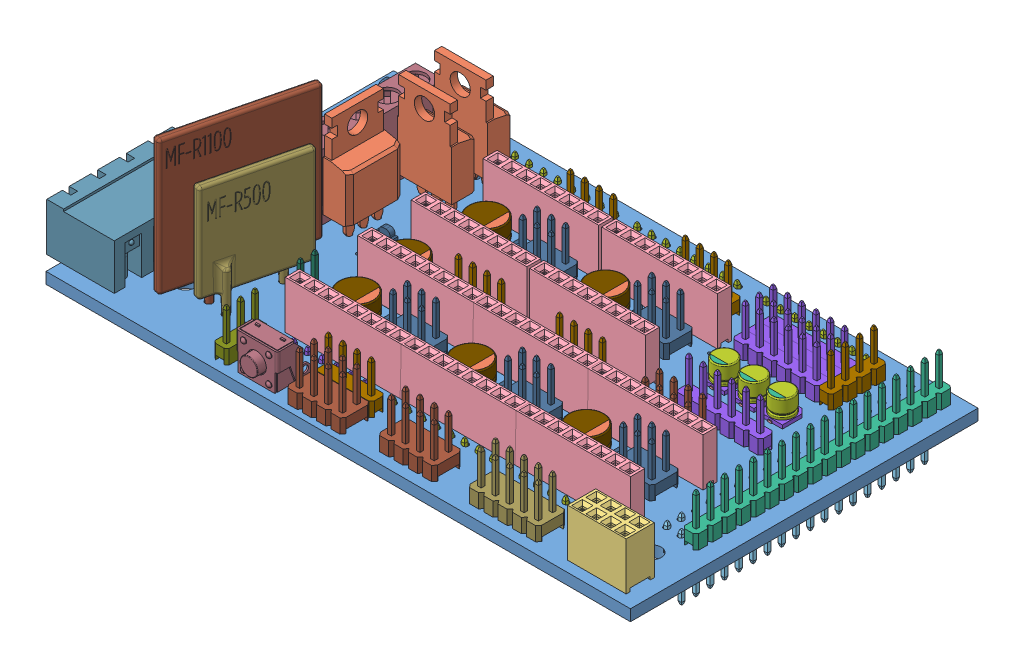
SolidWorks assembly RAMPS1_4, configuration Default. Lengths in mm.
Overall size (106.38 37.63 61.76).
107 component instances, 31 part files, 0 mates.
Components (placement in the parent):
- RAMPS1_4-1: RAMPS1_4 [Default] at (-38.4421 2.2803 -26.502) x (1 0 0) z (0 1 0) size (103.85 61.76 2)
- User Library-POWER MOSFET, NON-SURFACE-MOUNT-1: User Library-POWER MOSFET, NON-SURFACE-MOUNT [Default] at (-31.1839 8.1207 -13.4695) x (-1 0 0) z (0 -1 0) size (9.65 4.5 28.38)
- female_header_a-bl254-dg-g08d-1: female_header_a-bl254-dg-g08d [Default] at (41.0481 4.2584 25.6311) size (10.41 11.65 5)
- female_header_a-bl254-eg-g08d-2: female_header_a-bl254-eg-g08d [Default] at (6.3865 4.2963 -6.1397) size (20.57 11.65 2.5)
- female_header_a-bl254-eg-g08d-10: female_header_a-bl254-eg-g08d [Default] at (26.827 4.2963 16.9325) size (20.57 11.65 2.5)
- pin_header_aw254-dg-g36d-1: pin_header_aw254-dg-g36d [Default] at (40.9113 2.2239 -7.3898) x (0 0 1) z (-1 0 0) size (45.72 11.5 5.08)
- pin_header_aw140-eg-g18d-1: pin_header_aw140-eg-g18d [Default] at (44.7498 4.3175 -7.3949) x (0 0 -1) z (-1 0 0) size (45.62 11.2 2.5)
- pin_header_aw140-eg-g08d-1: pin_header_aw140-eg-g08d [Default] at (28.1033 2.2803 19.4616) size (20.22 11.2 2.5)
- pin_header_aw140-eg-g08d-2: pin_header_aw140-eg-g08d [Default] at (5.0609 2.2803 19.4616) size (20.22 11.2 2.5)
- pin_header_aw140-eg-g08d-3: pin_header_aw140-eg-g08d [Default] at (-0.0426 2.2803 -29.0108) size (20.22 11.2 2.5)
- pin_header_aw140-eg-g08d-4: pin_header_aw140-eg-g08d [Default] at (22.8713 2.2803 -29.0108) size (20.22 11.2 2.5)
- pin_header_aw140-eg-g08d-5: pin_header_aw140-eg-g08d [Default] at (-21.773 2.2803 -29.0108) size (20.22 11.2 2.5)
- pin_header_aw140-eg-g06d-1: pin_header_aw140-eg-g06d [Default] at (29.4382 4.2803 -6.1813) x (-1 0 0) z (0 0 1) size (15.14 11.2 2.5)
- pin_header_aw140-eg-g06d-2: pin_header_aw140-eg-g06d [Default] at (26.2798 4.262 -19.3796) x (-1 0 0) z (0 0 1) size (15.14 11.2 2.5)
- pin_header_aw140-eg-g04d-1: pin_header_aw140-eg-g04d [Default] at (8.4073 4.2803 -24.0519) x (-1 0 0) z (0 0 1) size (10.06 11.2 2.5)
- pin_header_aw140-eg-g04d-2: pin_header_aw140-eg-g04d [Default] at (-12.021 4.262 -24.0519) x (-1 0 0) z (0 0 1) size (10.06 11.2 2.5)
- pin_header_aw140-eg-g04d-3: pin_header_aw140-eg-g04d [Default] at (-8.9039 4.262 -1.0355) x (-1 0 0) z (0 0 1) size (10.06 11.2 2.5)
- pin_header_aw140-eg-g04d-4: pin_header_aw140-eg-g04d [Default] at (9.0685 4.262 -1.0355) x (-1 0 0) z (0 0 1) size (10.06 11.2 2.5)
- pin_header_aw140-eg-g04d-5: pin_header_aw140-eg-g04d [Default] at (-8.3709 4.2803 22.5944) x (-1 0 0) z (0 0 1) size (10.06 11.2 2.5)
- pin_header_aw254-dg-g06d-1: pin_header_aw254-dg-g06d [Default] at (-10.2573 4.2803 9.2323) x (-1 0 0) z (0 0 1) size (7.62 11.5 5.08)
- pin_header_aw254-dg-g06d-2: pin_header_aw254-dg-g06d [Default] at (10.1683 4.262 9.2323) x (-1 0 0) z (0 0 1) size (7.62 11.5 5.08)
- pin_header_aw254-dg-g06d-3: pin_header_aw254-dg-g06d [Default] at (30.6527 4.262 9.2323) x (-1 0 0) z (0 0 1) size (7.62 11.5 5.08)
- pin_header_aw254-dg-g06d-4: pin_header_aw254-dg-g06d [Default] at (10.1683 4.262 -13.7827) x (-1 0 0) z (0 0 1) size (7.62 11.5 5.08)
- pin_header_aw254-dg-g06d-5: pin_header_aw254-dg-g06d [Default] at (-10.2204 4.262 -13.7827) x (-1 0 0) z (0 0 1) size (7.62 11.5 5.08)
- pin_header_aw254-dg-g08d-1: pin_header_aw254-dg-g08d [Default] at (7.0775 4.2803 25.6017) x (-1 0 0) z (0 0 1) size (10.16 11.5 5.08)
- pin_header_aw254-dg-g08d-2: pin_header_aw254-dg-g08d [Default] at (-8.3884 4.2803 26.4286) x (-1 0 0) z (0 0 1) size (10.16 11.5 5.08)
- pin_header_aw254-dg-g10d-1: pin_header_aw254-dg-g10d [Default] at (24.3252 4.2803 25.6162) x (-1 0 0) z (0 0 1) size (12.7 11.5 5.08)
- pin_header_aw140-eg-g04d-6: pin_header_aw140-eg-g04d [Default] at (35.1498 4.262 -23.186) x (0 0 -1) z (-1 0 0) size (10.06 11.2 2.5)
- pin_header_aw140-eg-g06d-5: pin_header_aw140-eg-g06d [Default] at (-15.2568 2.2803 19.3514) size (15.14 11.2 2.5)
- terminal_blocks_a-tb500-to06-1: terminal_blocks_a-tb500-to06 [Default] at (-37.528 4.2803 -9.8658) x (0 0 1) z (-1 0 0) size (30.6 13.8 8.3)
- terminal_blocks_a-tb508-oq04ch-1: terminal_blocks_a-tb508-oq04ch [Default] at (-57.4712 4.2803 16.3679) x (0 0 1) z (-1 0 0) size (22.32 12.5 12)
- pin_header_aw254-dg-g08d-3: pin_header_aw254-dg-g08d [Default] at (26.8817 4.262 0.2918) x (-1 0 0) z (0 0 1) size (10.16 11.5 5.08)
- pin_header_aw140-eg-g02d-1: pin_header_aw140-eg-g02d [Default] at (-26.0896 4.2803 12.3888) x (0 0 1) z (1 0 0) size (4.98 11.2 2.5)
- pin_header_aw140-eg-g03d-1: pin_header_aw140-eg-g03d [Default] at (-25.5036 4.2803 24.8649) x (0 0 1) z (1 0 0) size (7.52 11.2 2.5)
- User Library-CAPSMD6_3x3_9-1: User Library-CAPSMD6_3x3_9 [Default] at (-23.4034 4.2803 -13.8521) x (0 0 -1) z (0 1 0) size (6.6 7 3.91)
  - User Library-CAPSMD6_3x3_9_CAP003-1: User Library-CAPSMD6_3x3_9_CAP003 [Default] at origin size (0.65 2.6 0.32)
  - User Library-CAPSMD6_3x3_9_CAP-1: User Library-CAPSMD6_3x3_9_CAP [Default] at origin size (6.3 6.3 3.26)
  - User Library-CAPSMD6_3x3_9_CAP001-1: User Library-CAPSMD6_3x3_9_CAP001 [Default] at origin size (6.6 6.6 0.64)
  - User Library-CAPSMD6_3x3_9_CAP002-1: User Library-CAPSMD6_3x3_9_CAP002 [Default] at origin size (5.11 1.47 0.01)
  - User Library-CAPSMD6_3x3_9_CAP004-1: User Library-CAPSMD6_3x3_9_CAP004 [Default] at origin size (0.65 2.6 0.32)
- User Library-CAPSMD6_3x3_9-2: User Library-CAPSMD6_3x3_9 [Default] at (-2.2688 4.2803 -13.8521) x (0 0 -1) z (0 1 0) size (6.6 7 3.91)
  - User Library-CAPSMD6_3x3_9_CAP003-1: User Library-CAPSMD6_3x3_9_CAP003 [Default] at origin size (0.65 2.6 0.32)
  - User Library-CAPSMD6_3x3_9_CAP-1: User Library-CAPSMD6_3x3_9_CAP [Default] at origin size (6.3 6.3 3.26)
  - User Library-CAPSMD6_3x3_9_CAP001-1: User Library-CAPSMD6_3x3_9_CAP001 [Default] at origin size (6.6 6.6 0.64)
  - User Library-CAPSMD6_3x3_9_CAP002-1: User Library-CAPSMD6_3x3_9_CAP002 [Default] at origin size (5.11 1.47 0.01)
  - User Library-CAPSMD6_3x3_9_CAP004-1: User Library-CAPSMD6_3x3_9_CAP004 [Default] at origin size (0.65 2.6 0.32)
- User Library-CAPSMD6_3x3_9-3: User Library-CAPSMD6_3x3_9 [Default] at (-2.8787 4.2803 9.2865) x (0 0 -1) z (0 1 0) size (6.6 7 3.91)
  - User Library-CAPSMD6_3x3_9_CAP003-1: User Library-CAPSMD6_3x3_9_CAP003 [Default] at origin size (0.65 2.6 0.32)
  - User Library-CAPSMD6_3x3_9_CAP-1: User Library-CAPSMD6_3x3_9_CAP [Default] at origin size (6.3 6.3 3.26)
  - User Library-CAPSMD6_3x3_9_CAP001-1: User Library-CAPSMD6_3x3_9_CAP001 [Default] at origin size (6.6 6.6 0.64)
  - User Library-CAPSMD6_3x3_9_CAP002-1: User Library-CAPSMD6_3x3_9_CAP002 [Default] at origin size (5.11 1.47 0.01)
  - User Library-CAPSMD6_3x3_9_CAP004-1: User Library-CAPSMD6_3x3_9_CAP004 [Default] at origin size (0.65 2.6 0.32)
- User Library-CAPSMD6_3x3_9-4: User Library-CAPSMD6_3x3_9 [Default] at (-23.2996 4.2803 9.2865) x (0 0 -1) z (0 1 0) size (6.6 7 3.91)
  - User Library-CAPSMD6_3x3_9_CAP003-1: User Library-CAPSMD6_3x3_9_CAP003 [Default] at origin size (0.65 2.6 0.32)
  - User Library-CAPSMD6_3x3_9_CAP-1: User Library-CAPSMD6_3x3_9_CAP [Default] at origin size (6.3 6.3 3.26)
  - User Library-CAPSMD6_3x3_9_CAP001-1: User Library-CAPSMD6_3x3_9_CAP001 [Default] at origin size (6.6 6.6 0.64)
  - User Library-CAPSMD6_3x3_9_CAP002-1: User Library-CAPSMD6_3x3_9_CAP002 [Default] at origin size (5.11 1.47 0.01)
  - User Library-CAPSMD6_3x3_9_CAP004-1: User Library-CAPSMD6_3x3_9_CAP004 [Default] at origin size (0.65 2.6 0.32)
- User Library-CAPSMD6_3x3_9-5: User Library-CAPSMD6_3x3_9 [Default] at (17.5196 4.2803 9.2865) x (0 0 -1) z (0 1 0) size (6.6 7 3.91)
  - User Library-CAPSMD6_3x3_9_CAP003-1: User Library-CAPSMD6_3x3_9_CAP003 [Default] at origin size (0.65 2.6 0.32)
  - User Library-CAPSMD6_3x3_9_CAP-1: User Library-CAPSMD6_3x3_9_CAP [Default] at origin size (6.3 6.3 3.26)
  - User Library-CAPSMD6_3x3_9_CAP001-1: User Library-CAPSMD6_3x3_9_CAP001 [Default] at origin size (6.6 6.6 0.64)
  - User Library-CAPSMD6_3x3_9_CAP002-1: User Library-CAPSMD6_3x3_9_CAP002 [Default] at origin size (5.11 1.47 0.01)
  - User Library-CAPSMD6_3x3_9_CAP004-1: User Library-CAPSMD6_3x3_9_CAP004 [Default] at origin size (0.65 2.6 0.32)
- User Library-CAPSMD6_3x3_9-6: User Library-CAPSMD6_3x3_9 [Default] at (-24.6073 4.2803 -1.0117) x (0 0 -1) z (0 1 0) size (6.6 7 3.91)
  - User Library-CAPSMD6_3x3_9_CAP003-1: User Library-CAPSMD6_3x3_9_CAP003 [Default] at origin size (0.65 2.6 0.32)
  - User Library-CAPSMD6_3x3_9_CAP-1: User Library-CAPSMD6_3x3_9_CAP [Default] at origin size (6.3 6.3 3.26)
  - User Library-CAPSMD6_3x3_9_CAP001-1: User Library-CAPSMD6_3x3_9_CAP001 [Default] at origin size (6.6 6.6 0.64)
  - User Library-CAPSMD6_3x3_9_CAP002-1: User Library-CAPSMD6_3x3_9_CAP002 [Default] at origin size (5.11 1.47 0.01)
  - User Library-CAPSMD6_3x3_9_CAP004-1: User Library-CAPSMD6_3x3_9_CAP004 [Default] at origin size (0.65 2.6 0.32)
- User Library-CAPSMD4x3_9-1: User Library-CAPSMD4x3_9 [Default] at (22.2937 4.2803 -15.1178) x (1 0 0) z (0 1 0) size (4.3 4.6 3.91)
  - User Library-CAPSMD4x3_9_CAPSMD4x3_9003-1: User Library-CAPSMD4x3_9_CAPSMD4x3_9003 [Default] at origin size (0.65 1.8 0.32)
  - User Library-CAPSMD4x3_9_CAPSMD4x3_9004-1: User Library-CAPSMD4x3_9_CAPSMD4x3_9004 [Default] at origin size (0.65 1.8 0.32)
  - User Library-CAPSMD4x3_9_CAPSMD4x3_9002-1: User Library-CAPSMD4x3_9_CAPSMD4x3_9002 [Default] at origin size (3.12 0.9 0.01)
  - User Library-CAPSMD4x3_9_CAPSMD4x3_9001-1: User Library-CAPSMD4x3_9_CAPSMD4x3_9001 [Default] at origin size (4 4 3.26)
  - User Library-CAPSMD4x3_9_CAPSMD4x3_9-1: User Library-CAPSMD4x3_9_CAPSMD4x3_9 [Default] at origin size (4.3 4.3 0.64)
- User Library-CAPSMD4x3_9-2: User Library-CAPSMD4x3_9 [Default] at (27.5508 4.2803 -15.1178) x (1 0 0) z (0 1 0) size (4.3 4.6 3.91)
  - User Library-CAPSMD4x3_9_CAPSMD4x3_9003-1: User Library-CAPSMD4x3_9_CAPSMD4x3_9003 [Default] at origin size (0.65 1.8 0.32)
  - User Library-CAPSMD4x3_9_CAPSMD4x3_9004-1: User Library-CAPSMD4x3_9_CAPSMD4x3_9004 [Default] at origin size (0.65 1.8 0.32)
  - User Library-CAPSMD4x3_9_CAPSMD4x3_9002-1: User Library-CAPSMD4x3_9_CAPSMD4x3_9002 [Default] at origin size (3.12 0.9 0.01)
  - User Library-CAPSMD4x3_9_CAPSMD4x3_9001-1: User Library-CAPSMD4x3_9_CAPSMD4x3_9001 [Default] at origin size (4 4 3.26)
  - User Library-CAPSMD4x3_9_CAPSMD4x3_9-1: User Library-CAPSMD4x3_9_CAPSMD4x3_9 [Default] at origin size (4.3 4.3 0.64)
- User Library-CAPSMD4x3_9-3: User Library-CAPSMD4x3_9 [Default] at (32.6212 4.2803 -15.1178) x (1 0 0) z (0 1 0) size (4.3 4.6 3.91)
  - User Library-CAPSMD4x3_9_CAPSMD4x3_9003-1: User Library-CAPSMD4x3_9_CAPSMD4x3_9003 [Default] at origin size (0.65 1.8 0.32)
  - User Library-CAPSMD4x3_9_CAPSMD4x3_9004-1: User Library-CAPSMD4x3_9_CAPSMD4x3_9004 [Default] at origin size (0.65 1.8 0.32)
  - User Library-CAPSMD4x3_9_CAPSMD4x3_9002-1: User Library-CAPSMD4x3_9_CAPSMD4x3_9002 [Default] at origin size (3.12 0.9 0.01)
  - User Library-CAPSMD4x3_9_CAPSMD4x3_9001-1: User Library-CAPSMD4x3_9_CAPSMD4x3_9001 [Default] at origin size (4 4 3.26)
  - User Library-CAPSMD4x3_9_CAPSMD4x3_9-1: User Library-CAPSMD4x3_9_CAPSMD4x3_9 [Default] at origin size (4.3 4.3 0.64)
- User Library-APA3010GCCK_GREEN-1: User Library-APA3010GCCK_GREEN [Default] at (-34.2243 4.3303 -27.7242) x (0 0 1) z (-1 0 0) size (3 2 1)
- User Library-APA3010GCCK_RED-1: User Library-APA3010GCCK_RED [Default] at (-49.6191 4.3303 -27.7242) x (0 0 1) z (-1 0 0) size (3 2 1)
- User Library-APA3010GCCK_RED-2: User Library-APA3010GCCK_RED [Default] at (-52.1602 4.3303 -27.7242) x (0 0 1) z (-1 0 0) size (3 2 1)
- User Library-MF-R1100___ _________-1: User Library-MF-R1100___ _________ [Default] at (-35.7942 -0.3428 15.0699) x (0 0 -1) z (0 -1 0) size (23.64 7.06 35.7)
- User Library-MF-R500___ _________-1: User Library-MF-R500___ _________ [Default] at (-32.5552 -0.5896 15.3075) x (0 0 -1) z (0 -1 0) size (17.04 5.43 29.1)
- User Library-SWITCH, TACTILE, RIGHT ANGLE, 12VDC, 50MA, 6_85MM ACTUATOR, WEALTH METAL TC-0244Z-1: User Library-SWITCH, TACTILE, RIGHT ANGLE, 12VDC, 50MA, 6_85MM ACTUATOR, WEALTH METAL TC-0244Z [Default] at (-19.0613 3.9803 23.5512) size (7.4 11 8)
- User Library-APA3010GCCK_RED-3: User Library-APA3010GCCK_RED [Default] at (-29.5185 4.3303 -5.1301) size (3 2 1)
- User Library-POWER MOSFET, NON-SURFACE-MOUNT-2: User Library-POWER MOSFET, NON-SURFACE-MOUNT [Default] at (-31.3941 8.433 -20.0341) x (-1 0 0) z (0 -1 0) size (9.65 4.5 28.38)
- User Library-POWER MOSFET, NON-SURFACE-MOUNT-3: User Library-POWER MOSFET, NON-SURFACE-MOUNT [Default] at (-36.1067 8.2823 -5.2135) x (0 0 -1) z (0 -1 0) size (9.65 4.5 28.38)
- female_header_a-bl254-eg-g08d-11: female_header_a-bl254-eg-g08d [Default] at (26.827 4.2963 4.0825) size (20.57 11.65 2.5)
- female_header_a-bl254-eg-g08d-12: female_header_a-bl254-eg-g08d [Default] at (6.417 4.2963 16.9325) size (20.57 11.65 2.5)
- female_header_a-bl254-eg-g08d-13: female_header_a-bl254-eg-g08d [Default] at (6.417 4.2963 4.0825) size (20.57 11.65 2.5)
- female_header_a-bl254-eg-g08d-14: female_header_a-bl254-eg-g08d [Default] at (-13.993 4.2963 16.9325) size (20.57 11.65 2.5)
- female_header_a-bl254-eg-g08d-15: female_header_a-bl254-eg-g08d [Default] at (-13.993 4.2963 4.0825) size (20.57 11.65 2.5)
- female_header_a-bl254-eg-g08d-16: female_header_a-bl254-eg-g08d [Default] at (6.3865 4.2963 -18.9097) size (20.57 11.65 2.5)
- female_header_a-bl254-eg-g08d-17: female_header_a-bl254-eg-g08d [Default] at (-14.6935 4.2963 -6.1397) size (20.57 11.65 2.5)
- female_header_a-bl254-eg-g08d-18: female_header_a-bl254-eg-g08d [Default] at (-14.6935 4.2963 -18.9097) size (20.57 11.65 2.5)
- pin_header_aw140-eg-g06d-6: pin_header_aw140-eg-g06d [Default] at (26.2798 4.262 -21.8496) x (-1 0 0) z (0 0 1) size (15.14 11.2 2.5)
- pin_header_aw140-eg-g06d-7: pin_header_aw140-eg-g06d [Default] at (26.2798 4.262 -24.3196) x (-1 0 0) z (0 0 1) size (15.14 11.2 2.5)
